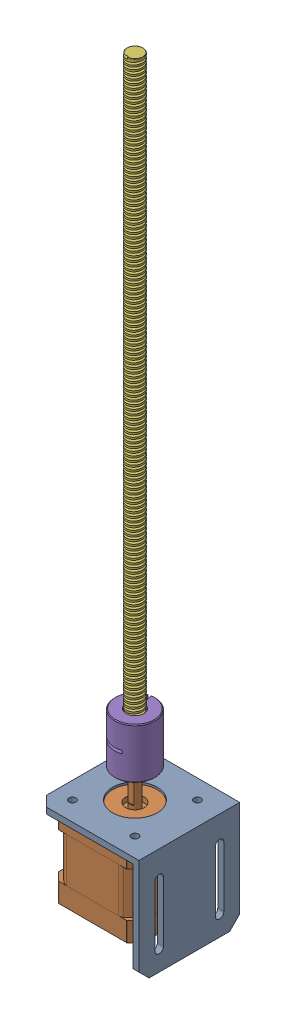
SolidWorks assembly Z lead screw assembly, configuration Default. Lengths in mm.
Overall size (53.08 374.6 50).
4 component instances, 4 part files, 10 mates.
Components (placement in the parent):
- nema17 stepper motor 90 degree mount-1: nema17 stepper motor 90 degree mount [Default] at (0 0 50) x (0 0 1) z (0 -1 0) size (50 51 53)
- NEMA17 42-40-1: NEMA17 42-40 [Default] at (-27 50 25) x (0 0 -1) z (-1 0 0) size (42 63.75 47.08)
- 5x8_Rigid_Coupling_20x25-1: 5x8_Rigid_Coupling_20x25 [По умолчанию] at (-27 67.352 25) x (-0.234072 0 -0.972219) z (0 1 0) size (20.11 20 25)
- LeadScrew 8mm x 2mmPitch-1: LeadScrew 8mm x 2mmPitch [Default] at (-27 74.352 25) x (0.998637 0 -0.052186) z (0 -1 0) size (9.24 8.22 301.1)
Mates (geometry in assembly coordinates):
- Coincident1: coincident aligned: plane of nema17 stepper motor 90 degree mount-1 through (0 53 0) normal (1 0 0)
- Coincident2: coincident anti-aligned: plane of nema17 stepper motor 90 degree mount-1 through (0 0 0) normal (0 0 -1)
- Coincident3: coincident anti-aligned: plane of nema17 stepper motor 90 degree mount-1 through (0 0 0) normal (0 -1 0)
- Coincident4: coincident anti-aligned: plane of nema17 stepper motor 90 degree mount-1 through (-3 50 0) normal (0 -1 0); plane of NEMA17 42-40-1 through (-27 50 25) normal (0 1 0)
- Concentric1: concentric aligned: cylinder of nema17 stepper motor 90 degree mount-1 through (-27 53.001 25) axis (0 -1 0) radius 11.05; cylinder of NEMA17 42-40-1 through (-27 52 25) axis (0 -1 0) radius 11
- Concentric2: concentric aligned: cylinder of nema17 stepper motor 90 degree mount-1 through (-42.5 53.001 40.5) axis (0 -1 0) radius 1.75; cylinder of NEMA17 42-40-1 through (-42.5 50 40.5) axis (0 -1 0) radius 1.2295
- Concentric4: concentric aligned: cylinder of NEMA17 42-40-1 through (-27 74.352 25) axis (0 -1 0) radius 2.5; cylinder of 5x8_Rigid_Coupling_20x25-1 through (-27 92.352 25) axis (0 -1 0) radius 10
- Coincident7: coincident aligned: plane of NEMA17 42-40-1 through (-27 74.352 25) normal (0 1 0); plane of 5x8_Rigid_Coupling_20x25-1 through (-27 74.352 25) normal (0 1 0)
- Concentric5: concentric anti-aligned: cylinder of 5x8_Rigid_Coupling_20x25-1 through (-27 92.352 25) axis (0 -1 0) radius 4; circle of LeadScrew 8mm x 2mmPitch-1
- Coincident8: coincident anti-aligned: plane of 5x8_Rigid_Coupling_20x25-1 through (-27 74.352 25) normal (0 1 0); plane of LeadScrew 8mm x 2mmPitch-1 through (-27 74.352 25) normal (0 -1 0)
